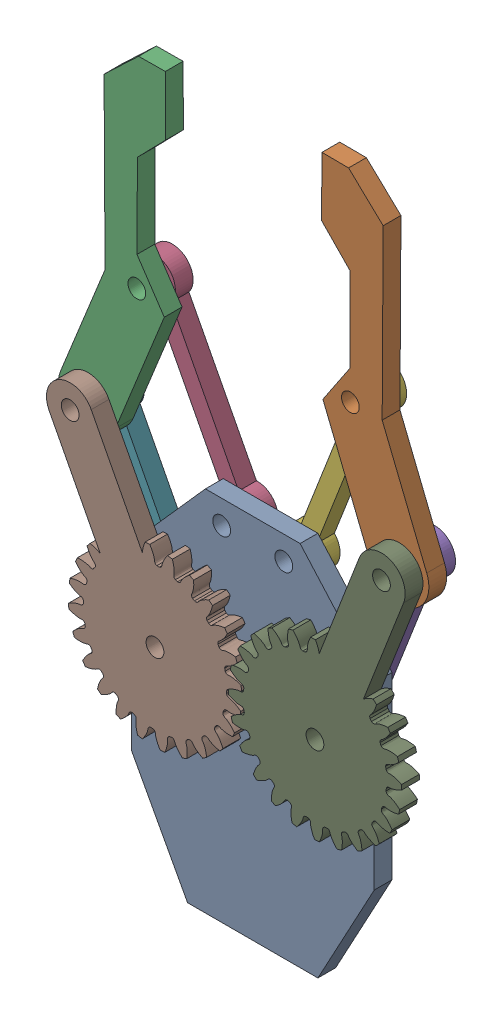
SolidWorks assembly 舵机夹爪, configuration 默认. Lengths in mm.
Overall size (85.65 123.83 9).
9 component instances, 4 part files, 21 mates.
Components (placement in the parent):
- 零件3-1: 零件3 [默认] at (-0.7619 -33.0634 0) size (41 62 3)
- 零件1-1: 零件1 [默认] at (23.9643 33.4322 3) x (-0.374898 0.927066 0) z (0 0 -1) size (60.44 20.84 3)
- 零件1-2: 零件1 [默认] at (-28.5733 32.0351 0) x (0.374978 0.927034 0) z (0 0 1) size (60.44 20.84 3)
- 零件2-1: 零件2 [默认] at (-6.0017 24.9366 -3) x (-0.462002 0.886879 0) z (0 0 1) size (38 7 3)
- 零件2-2: 零件2 [默认] at (12.7381 4.5364 -3) x (0.362135 0.932126 0) z (0 0 1) size (38 7 3)
- 零件2-3: 零件2 [默认] at (4.478 24.9366 -3) x (0.362536 0.93197 0) z (0 0 1) size (38 7 3)
- 零件2-4: 零件2 [默认] at (-14.2619 4.5364 -3) x (-0.461658 0.887058 0) z (0 0 1) size (38 7 3)
- 零件4-1: 零件4 [默认] at (-14.2619 4.5364 3) x (0.461658 -0.887058 0) z (0 0 1) size (49.55 29.09 3)
- 零件4-2: 零件4 [默认] at (12.7381 4.5364 3) x (-0.362135 -0.932126 0) z (0 0 1) size (49.55 29.09 3)
Mates (geometry in assembly coordinates):
- 重合2: coincident aligned: plane of 零件3-1 through (-0.7619 -33.0634 3) normal (0 0 1); plane of 零件1-1 through (23.9643 33.4322 3) normal (0 0 1)
- 重合3: coincident anti-aligned: plane of 零件3-1 through (-0.7619 -33.0634 0) normal (0 0 -1); plane of 零件2-4 through (-14.2619 4.5364 0) normal (0 0 1)
- 重合4: coincident anti-aligned: plane of 零件3-1 through (-0.7619 -33.0634 0) normal (0 0 -1); plane of 零件2-2 through (12.7381 4.5364 0) normal (0 0 1)
- 重合5: coincident anti-aligned: plane of 零件3-1 through (-0.7619 -33.0634 0) normal (0 0 -1); plane of 零件2-1 through (-6.0017 24.9366 0) normal (0 0 1)
- 重合6: coincident anti-aligned: plane of 零件3-1 through (-0.7619 -33.0634 0) normal (0 0 -1); plane of 零件2-3 through (4.478 24.9366 0) normal (0 0 1)
- 同心1: concentric aligned: cylinder of 零件3-1 through (-6.0017 24.9366 3) axis (0 0 -1) radius 1.5; cylinder of 零件2-1 through (-6.0017 24.9366 0) axis (0 0 -1) radius 1.5
- 同心2: concentric aligned: cylinder of 零件3-1 through (4.478 24.9366 3) axis (0 0 -1) radius 1.5; cylinder of 零件2-3 through (4.478 24.9366 0) axis (0 0 -1) radius 1.5
- 同心3: concentric aligned: cylinder of 零件3-1 through (12.7381 4.5364 3) axis (0 0 -1) radius 1.5; cylinder of 零件2-2 through (12.7381 4.5364 0) axis (0 0 -1) radius 1.5
- 同心4: concentric aligned: cylinder of 零件3-1 through (-14.2619 4.5364 3) axis (0 0 -1) radius 1.5; cylinder of 零件2-4 through (-14.2619 4.5364 0) axis (0 0 -1) radius 1.5
- 同心5: concentric anti-aligned: cylinder of 零件1-1 through (23.9643 33.4322 0) axis (0 0 1) radius 1.5; cylinder of 零件2-2 through (23.9643 33.4322 0) axis (0 0 -1) radius 1.5
- 同心6: concentric anti-aligned: cylinder of 零件1-1 through (15.7166 53.8277 0) axis (0 0 1) radius 1.5; cylinder of 零件2-3 through (15.7166 53.8277 0) axis (0 0 -1) radius 1.5
- 重合10: coincident aligned: plane of 零件3-1 through (-0.7619 -33.0634 3) normal (0 0 1); plane of 零件1-2 through (-28.5733 32.0351 3) normal (0 0 1)
- 同心7: concentric aligned: cylinder of 零件1-2 through (-28.5733 32.0351 3) axis (0 0 -1) radius 1.5; cylinder of 零件2-4 through (-28.5733 32.0351 0) axis (0 0 -1) radius 1.5
- 同心8: concentric aligned: cylinder of 零件1-2 through (-20.3237 52.4299 3) axis (0 0 -1) radius 1.5; cylinder of 零件2-1 through (-20.3237 52.4299 0) axis (0 0 -1) radius 1.5
- 重合11: coincident anti-aligned: plane of 零件3-1 through (-0.7619 -33.0634 3) normal (0 0 1); plane of 零件4-2 through (12.7381 4.5364 3) normal (0 0 -1)
- 重合12: coincident anti-aligned: plane of 零件3-1 through (-0.7619 -33.0634 3) normal (0 0 1); plane of 零件4-1 through (-14.2619 4.5364 3) normal (0 0 -1)
- 同心9: concentric anti-aligned: cylinder of 零件3-1 through (12.7381 4.5364 3) axis (0 0 -1) radius 1.5; cylinder of 零件4-2 through (12.7381 4.5364 3) axis (0 0 1) radius 1.5
- 重合13: coincident anti-aligned: circle of 零件1-1; cylinder of 零件4-2 through (23.9643 33.4322 3) axis (0 0 1) radius 1.5
- 重合14: coincident anti-aligned: cylinder of 零件3-1 through (-14.2619 4.5364 3) axis (0 0 -1) radius 1.5; circle of 零件4-1
- 重合15: coincident aligned: circle of 零件1-2; circle of 零件4-1
- 齿轮配合1: gear = 27 : 27 mm: circle of 零件4-1; circle of 零件4-2
